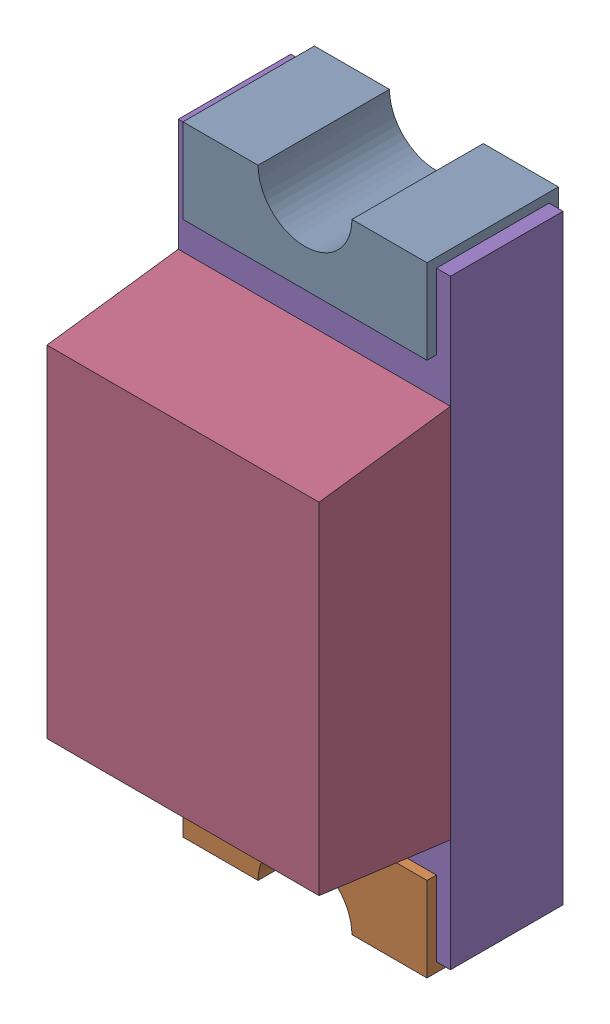
SolidWorks assembly P3, configuration Standard. Lengths in mm.
Overall size (0.73 1.65 0.68).
6 component instances, 5 part files, 0 mates.
Components (placement in the parent):
- P3-subassembly-1-1: P3-subassembly-1 [Standard] at (1.4001 16.1499 0) x (1 0 0) z (0 0 1) size (0.72 1.65 0.68)
  - User Library-LED SMD0603-1: User Library-LED SMD0603 [Standard] at origin size (0.65 0.28 0.35)
  - User Library-LED SMD0603-1-1: User Library-LED SMD0603-1 [Standard] at origin size (0.65 0.28 0.35)
  - User Library-LED SMD0603-2-1: User Library-LED SMD0603-2 [Standard] at origin size (0.15 0.16 0.07)
  - User Library-LED SMD0603-3-1: User Library-LED SMD0603-3 [Standard] at origin size (0.72 1 0.35)
  - User Library-LED SMD0603-4-1: User Library-LED SMD0603-4 [Standard] at origin size (0.72 1.6 0.3)
